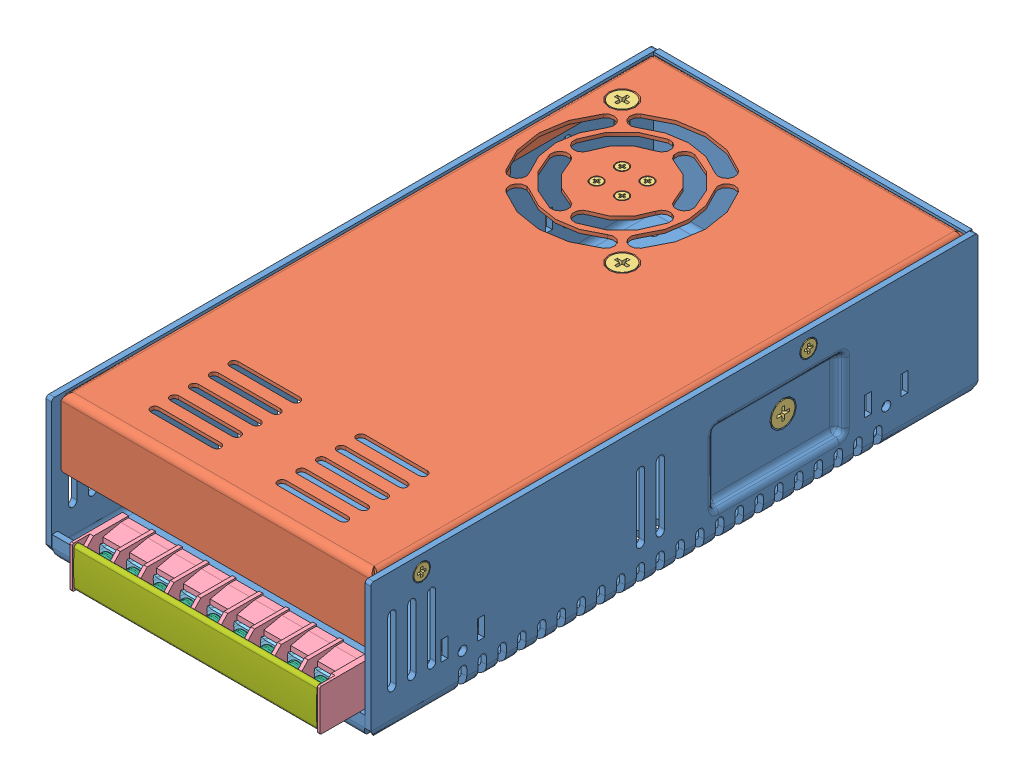
SolidWorks assembly Mean Well QP-320D Quad Power Supply, configuration Default. Lengths in mm.
Overall size (115.1 50.01 229.07).
38 component instances, 7 part files, 3 mates.
Components (placement in the parent):
- Enclosure of Mean Well QP-320D Quad Power Supply-1: Enclosure of Mean Well QP-320D Quad Power Supply [Default] at origin size (115.1 50.01 215.37)
  - Bottom of Enclosure of Mean Well QP-320D Quad Power Supply-1: Bottom of Enclosure of Mean Well QP-320D Quad Power Supply [Default] at (-42.7955 -32.6738 29.1784) size (115.04 49.51 215.36)
  - Top of Enclosure of Mean Well QP-320D Quad Power Supply-1: Top of Enclosure of Mean Well QP-320D Quad Power Supply [Default] at (-42.7955 14.1262 28.7784) x (1 0 0) z (0 0 -1) size (110.84 24 209.81)
  - flat head screw_am-17: flat head screw_am [B18.6.7M - M3 x 0.5 x 5 Type I Cross Recessed FHMS --5N] at (14.7545 9.3262 118.6784) x (-1 0 0) z (0 0 -1) size (5 5.5 5.5)
  - flat head screw_am-18: flat head screw_am [B18.6.7M - M3 x 0.5 x 5 Type I Cross Recessed FHMS --5N] at (14.7545 9.3262 -18.3216) x (-1 0 0) z (0 0 -1) size (5 5.5 5.5)
  - flat head screw_am-5: flat head screw_am [B18.6.7M - M4 x 0.7 x 8 Type I Cross Recessed FHMS --8N] at (11.7045 -9.1738 -12.3216) x (-1 0 0) z (0 0 -1) size (8 8.4 8.4)
  - flat head screw_am-6: flat head screw_am [B18.6.7M - M4 x 0.7 x 8 Type I Cross Recessed FHMS --8N] at (-29.5256 -9.1738 -75.3216) x (0 0 1) z (-1 0 0) size (8 8.4 8.4)
  - flat head screw_am-7: flat head screw_am [B18.6.7M - M3 x 0.5 x 5 Type I Cross Recessed FHMS --5N] at (2.4545 9.3262 -78.3716) x (0 0 1) z (-1 0 0) size (5 5.5 5.5)
  - flat head screw_am-8: flat head screw_am [B18.6.7M - M3 x 0.5 x 5 Type I Cross Recessed FHMS --5N] at (-88.0455 9.3262 -78.3716) x (0 0 1) z (-1 0 0) size (5 5.5 5.5)
  - flat head screw_am-9: flat head screw_am [B18.6.7M - M3 x 0.5 x 5 Type I Cross Recessed FHMS --5N] at (-100.3455 9.3262 -18.3216) size (5 5.5 5.5)
  - flat head screw_am-10: flat head screw_am [B18.6.7M - M3 x 0.5 x 5 Type I Cross Recessed FHMS --5N] at (-100.3455 9.3262 118.6784) size (5 5.5 5.5)
  - flat head screw_am-11: flat head screw_am [B18.6.7M - M4 x 0.7 x 8 Type I Cross Recessed FHMS --8N] at (-88.5955 15.3262 -55.6216) x (0 -1 0) z (0 0 1) size (8 8.4 8.4)
  - flat head screw_am-12: flat head screw_am [B18.6.7M - M4 x 0.7 x 8 Type I Cross Recessed FHMS --8N] at (-38.5955 15.3262 -5.6216) x (0 -1 0) z (0 0 1) size (8 8.4 8.4)
  - flat head screw_am-13: flat head screw_am [B18.6.7M - M2 x 0.4 x 3 Type I Cross Recessed FHMS --3N] at (-68.0955 15.3262 -35.1216) x (0 -1 0) z (0 0 1) size (3 3.8 3.8)
  - flat head screw_am-14: flat head screw_am [B18.6.7M - M2 x 0.4 x 3 Type I Cross Recessed FHMS --3N] at (-59.0955 15.3262 -35.1216) x (0 -1 0) z (0 0 1) size (3 3.8 3.8)
  - flat head screw_am-15: flat head screw_am [B18.6.7M - M2 x 0.4 x 3 Type I Cross Recessed FHMS --3N] at (-59.0955 15.3262 -26.1216) x (0 -1 0) z (0 0 1) size (3 3.8 3.8)
  - flat head screw_am-16: flat head screw_am [B18.6.7M - M2 x 0.4 x 3 Type I Cross Recessed FHMS --3N] at (-68.0955 15.3262 -26.1216) x (0 -1 0) z (0 0 1) size (3 3.8 3.8)
- Switchlab T14-EO33-09 Terminal Block-1: Switchlab T14-EO33-09 Terminal Block [Default] at (-27.9072 69.1762 133.5574) x (1 0 0) z (0 -1 0) size (88.5 18.62 14.7)
  - Body of Switchlab T14-EO33-09 Terminal Block-1: Body of Switchlab T14-EO33-09 Terminal Block [Default] at (-5.6384 -1.479 88.5) size (88.5 18.6 14.7)
  - Clamp Plate of Switchlab T14-EO33-09 Terminal Block-1: Clamp Plate of Switchlab T14-EO33-09 Terminal Block [Default] at (-43.6384 9.0158 88.5) size (8.4 1.4 8.4)
  - Philips-Drive Panhead Screw of Switchlab T14-EO33-09 Terminal Block-1: Philips-Drive Panhead Screw of Switchlab T14-EO33-09 Terminal Block [92000A151] at (-43.6384 3.0158 88.5) x (1 0 0) z (0 1 0) size (7 7 8.8)
  - Philips-Drive Panhead Screw of Switchlab T14-EO33-09 Terminal Block-2: Philips-Drive Panhead Screw of Switchlab T14-EO33-09 Terminal Block [92000A151] at (-34.1384 3.0158 88.5) x (1 0 0) z (0 1 0) size (7 7 8.8)
  - Philips-Drive Panhead Screw of Switchlab T14-EO33-09 Terminal Block-3: Philips-Drive Panhead Screw of Switchlab T14-EO33-09 Terminal Block [92000A151] at (-24.6384 3.0158 88.5) x (1 0 0) z (0 1 0) size (7 7 8.8)
  - Philips-Drive Panhead Screw of Switchlab T14-EO33-09 Terminal Block-4: Philips-Drive Panhead Screw of Switchlab T14-EO33-09 Terminal Block [92000A151] at (-15.1384 3.0158 88.5) x (1 0 0) z (0 1 0) size (7 7 8.8)
  - Philips-Drive Panhead Screw of Switchlab T14-EO33-09 Terminal Block-5: Philips-Drive Panhead Screw of Switchlab T14-EO33-09 Terminal Block [92000A151] at (-5.6384 3.0158 88.5) x (1 0 0) z (0 1 0) size (7 7 8.8)
  - Philips-Drive Panhead Screw of Switchlab T14-EO33-09 Terminal Block-6: Philips-Drive Panhead Screw of Switchlab T14-EO33-09 Terminal Block [92000A151] at (3.8616 3.0158 88.5) x (1 0 0) z (0 1 0) size (7 7 8.8)
  - Philips-Drive Panhead Screw of Switchlab T14-EO33-09 Terminal Block-7: Philips-Drive Panhead Screw of Switchlab T14-EO33-09 Terminal Block [92000A151] at (13.3616 3.0158 88.5) x (1 0 0) z (0 1 0) size (7 7 8.8)
  - Philips-Drive Panhead Screw of Switchlab T14-EO33-09 Terminal Block-8: Philips-Drive Panhead Screw of Switchlab T14-EO33-09 Terminal Block [92000A151] at (22.8616 3.0158 88.5) x (1 0 0) z (0 1 0) size (7 7 8.8)
  - Philips-Drive Panhead Screw of Switchlab T14-EO33-09 Terminal Block-9: Philips-Drive Panhead Screw of Switchlab T14-EO33-09 Terminal Block [92000A151] at (32.3616 3.0158 88.5) x (1 0 0) z (0 1 0) size (7 7 8.8)
  - Clamp Plate of Switchlab T14-EO33-09 Terminal Block-2: Clamp Plate of Switchlab T14-EO33-09 Terminal Block [Default] at (-34.1384 9.0158 88.5) size (8.4 1.4 8.4)
  - Clamp Plate of Switchlab T14-EO33-09 Terminal Block-3: Clamp Plate of Switchlab T14-EO33-09 Terminal Block [Default] at (-24.6384 9.0158 88.5) size (8.4 1.4 8.4)
  - Clamp Plate of Switchlab T14-EO33-09 Terminal Block-4: Clamp Plate of Switchlab T14-EO33-09 Terminal Block [Default] at (-15.1384 9.0158 88.5) size (8.4 1.4 8.4)
  - Clamp Plate of Switchlab T14-EO33-09 Terminal Block-5: Clamp Plate of Switchlab T14-EO33-09 Terminal Block [Default] at (-5.6384 9.0158 88.5) size (8.4 1.4 8.4)
  - Clamp Plate of Switchlab T14-EO33-09 Terminal Block-6: Clamp Plate of Switchlab T14-EO33-09 Terminal Block [Default] at (3.8616 9.0158 88.5) size (8.4 1.4 8.4)
  - Clamp Plate of Switchlab T14-EO33-09 Terminal Block-7: Clamp Plate of Switchlab T14-EO33-09 Terminal Block [Default] at (13.3616 9.0158 88.5) size (8.4 1.4 8.4)
  - Clamp Plate of Switchlab T14-EO33-09 Terminal Block-8: Clamp Plate of Switchlab T14-EO33-09 Terminal Block [Default] at (22.8616 9.0158 88.5) size (8.4 1.4 8.4)
  - Clamp Plate of Switchlab T14-EO33-09 Terminal Block-9: Clamp Plate of Switchlab T14-EO33-09 Terminal Block [Default] at (32.3616 9.0158 88.5) size (8.4 1.4 8.4)
  - Cover for Switchlab T14-EO33-09 Terminal Block-1: Cover for Switchlab T14-EO33-09 Terminal Block [Default] at (-5.6384 17.141 88.3265) size (86 2.95 14)
Mates (geometry in assembly coordinates):
- Distance1: distance = 4 mm aligned: plane of Switchlab T14-EO33-09 Terminal Block-1/Body of Switchlab T14-EO33-09 Terminal Block-1 through (10.7045 -19.3238 132.0784) normal (1 0 0); plane of Enclosure of Mean Well QP-320D Quad Power Supply-1/Bottom of Enclosure of Mean Well QP-320D Quad Power Supply-1 through (14.7045 -32.6738 29.1784) normal (1 0 0)
- Coincident2: coincident anti-aligned: plane of Enclosure of Mean Well QP-320D Quad Power Supply-1/Bottom of Enclosure of Mean Well QP-320D Quad Power Supply-1 through (-42.7955 -26.6738 -78.3276) normal (0 1 0); plane of Switchlab T14-EO33-09 Terminal Block-1/Body of Switchlab T14-EO33-09 Terminal Block-1 through (-76.9455 -26.6738 150.1784) normal (0 -1 0)
- Distance2: distance = 14 mm aligned: plane of Switchlab T14-EO33-09 Terminal Block-1/Body of Switchlab T14-EO33-09 Terminal Block-1 through (9.8545 -12.4738 150.6784) normal (0 0 1); plane of Enclosure of Mean Well QP-320D Quad Power Supply-1/Bottom of Enclosure of Mean Well QP-320D Quad Power Supply-1 through (14.7045 -30.6738 136.6784) normal (0 0 1)
